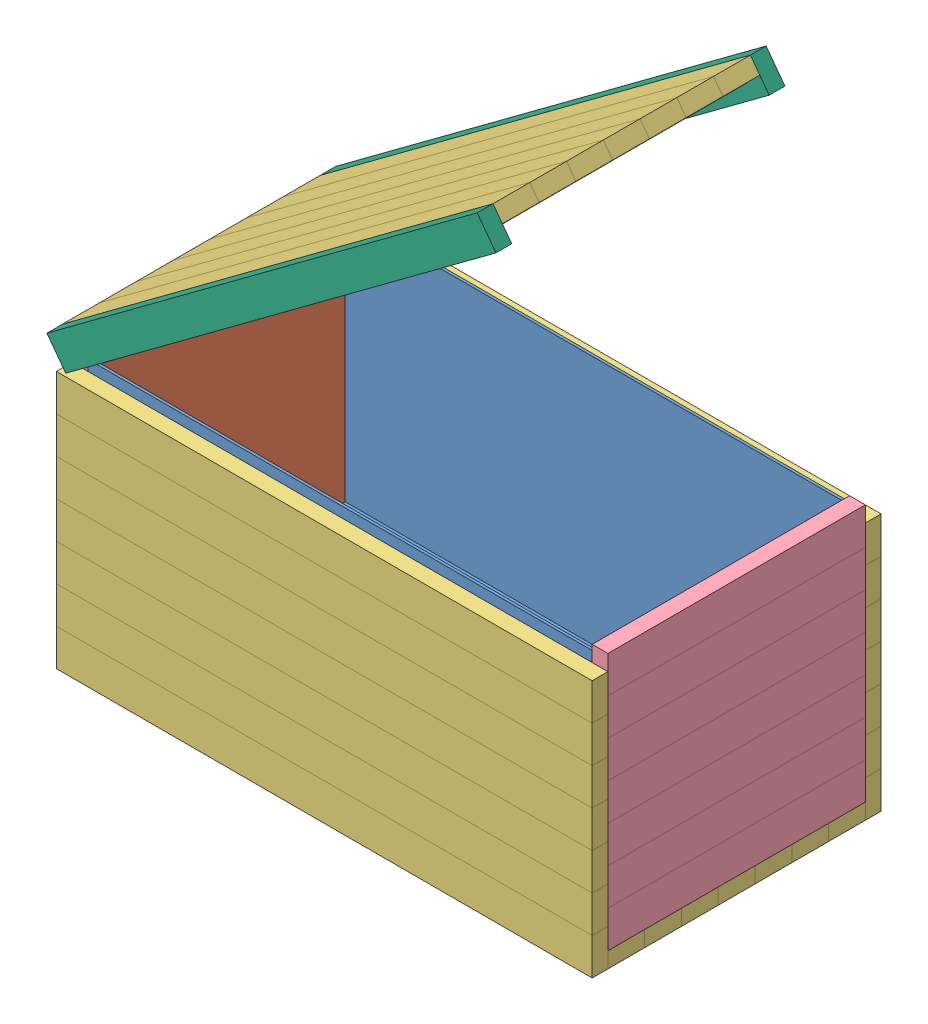
SolidWorks assembly box, configuration Default. Lengths in mm.
Overall size (1331.52 1463.02 698.5).
58 component instances, 8 part files, 31 mates.
Components (placement in the parent):
- plywood_base-1: plywood_base [Default] at (42.8418 78.5863 -75.9974) size (1219.2 6.35 609.6)
- plywood_base-2: plywood_base [Default] at (42.8418 383.3863 228.8026) x (1 0 0) z (0 -1 0) size (1219.2 6.35 609.6)
- plywood_base-3: plywood_base [Default] at (42.8418 383.3863 -380.7974) x (1 0 0) z (0 1 0) size (1219.2 6.35 609.6)
- plywood_short_side-1: plywood_short_side [Default] at (-560.4082 389.7363 -75.9974) x (0 0 1) z (-1 0 0) size (609.6 609.6 6.35)
- plywood_short_side-2: plywood_short_side [Default] at (646.0918 389.7363 -75.9974) x (0 0 -1) z (1 0 0) size (609.6 609.6 6.35)
- long_side-1: long_side [Default] at (-24.755 320.4343 -387.3917) x (1 0 0) z (0 -1 0) size (1295.4 38.1 622.3)
  - 51in_2x4-1: 51in_2x4 [Default] at (-580.1032 -18.8057 235.4979) x (0 0 -1) z (1 0 0) size (88.9 38.1 1295.4)
  - 51in_2x4-2: 51in_2x4 [Default] at (-580.1032 -18.8057 146.5979) x (0 0 -1) z (1 0 0) size (88.9 38.1 1295.4)
  - 51in_2x4-3: 51in_2x4 [Default] at (715.2968 -18.8057 -297.9021) x (0 0 1) z (-1 0 0) size (88.9 38.1 1295.4)
  - 51in_2x4-4: 51in_2x4 [Default] at (715.2968 -18.8057 57.6979) x (0 0 1) z (-1 0 0) size (88.9 38.1 1295.4)
  - 51in_2x4-5: 51in_2x4 [Default] at (715.2968 -18.8057 -31.2021) x (0 0 1) z (-1 0 0) size (88.9 38.1 1295.4)
  - 51in_2x4-6: 51in_2x4 [Default] at (715.2968 -18.8057 -120.1021) x (0 0 1) z (-1 0 0) size (88.9 38.1 1295.4)
  - 51in_2x4-7: 51in_2x4 [Default] at (715.2968 -18.8057 -209.0021) x (0 0 1) z (-1 0 0) size (88.9 38.1 1295.4)
- long_side-2: long_side [Default] at (-24.755 382.8384 235.3968) x (1 0 0) z (0 1 0) size (1295.4 38.1 622.3)
  - 51in_2x4-1: 51in_2x4 [Default] at (-580.1032 -18.8057 235.4979) x (0 0 -1) z (1 0 0) size (88.9 38.1 1295.4)
  - 51in_2x4-2: 51in_2x4 [Default] at (-580.1032 -18.8057 146.5979) x (0 0 -1) z (1 0 0) size (88.9 38.1 1295.4)
  - 51in_2x4-3: 51in_2x4 [Default] at (715.2968 -18.8057 -297.9021) x (0 0 1) z (-1 0 0) size (88.9 38.1 1295.4)
  - 51in_2x4-4: 51in_2x4 [Default] at (715.2968 -18.8057 57.6979) x (0 0 1) z (-1 0 0) size (88.9 38.1 1295.4)
  - 51in_2x4-5: 51in_2x4 [Default] at (715.2968 -18.8057 -31.2021) x (0 0 1) z (-1 0 0) size (88.9 38.1 1295.4)
  - 51in_2x4-6: 51in_2x4 [Default] at (715.2968 -18.8057 -120.1021) x (0 0 1) z (-1 0 0) size (88.9 38.1 1295.4)
  - 51in_2x4-7: 51in_2x4 [Default] at (715.2968 -18.8057 -209.0021) x (0 0 1) z (-1 0 0) size (88.9 38.1 1295.4)
- long_side-3: long_side [Default] at (-24.755 78.3421 -44.7953) size (1295.4 38.1 622.3)
  - 51in_2x4-1: 51in_2x4 [Default] at (-580.1032 -18.8057 235.4979) x (0 0 -1) z (1 0 0) size (88.9 38.1 1295.4)
  - 51in_2x4-2: 51in_2x4 [Default] at (-580.1032 -18.8057 146.5979) x (0 0 -1) z (1 0 0) size (88.9 38.1 1295.4)
  - 51in_2x4-3: 51in_2x4 [Default] at (715.2968 -18.8057 -297.9021) x (0 0 1) z (-1 0 0) size (88.9 38.1 1295.4)
  - 51in_2x4-4: 51in_2x4 [Default] at (715.2968 -18.8057 57.6979) x (0 0 1) z (-1 0 0) size (88.9 38.1 1295.4)
  - 51in_2x4-5: 51in_2x4 [Default] at (715.2968 -18.8057 -31.2021) x (0 0 1) z (-1 0 0) size (88.9 38.1 1295.4)
  - 51in_2x4-6: 51in_2x4 [Default] at (715.2968 -18.8057 -120.1021) x (0 0 1) z (-1 0 0) size (88.9 38.1 1295.4)
  - 51in_2x4-7: 51in_2x4 [Default] at (715.2968 -18.8057 -209.0021) x (0 0 1) z (-1 0 0) size (88.9 38.1 1295.4)
- short_side-2: short_side [Default] at (300.1716 281.9142 -332.5082) x (0 -1 0) z (0 0 1) size (622.3 38.1 622.3)
  - 24in_2x4-1: 24in_2x4 [Default] at (-374.5222 371.3202 -54.6392) size (88.9 38.1 622.3)
  - 24in_2x4-2: 24in_2x4 [Default] at (-285.6222 371.3202 -54.6392) size (88.9 38.1 622.3)
  - 24in_2x4-3: 24in_2x4 [Default] at (-196.7222 371.3202 -54.6392) size (88.9 38.1 622.3)
  - 24in_2x4-4: 24in_2x4 [Default] at (-107.8222 371.3202 -54.6392) size (88.9 38.1 622.3)
  - 24in_2x4-5: 24in_2x4 [Default] at (69.9778 371.3202 -54.6392) size (88.9 38.1 622.3)
  - 24in_2x4-6: 24in_2x4 [Default] at (158.8778 371.3202 -54.6392) size (88.9 38.1 622.3)
  - 24in_2x4-8: 24in_2x4 [Default] at (-18.9222 371.3202 -54.6392) size (88.9 38.1 622.3)
- lid-1: lid [Default] at (-111.6526 1036.7887 -32.7455) x (0.803005 0.595972 0) z (0 0 1) size (1295.4 76.2 698.5)
  - plywood_lid-1: plywood_lid [Default] at (50.5401 17.8556 -38.8001) size (1219.2 6.35 622.3)
  - long_side-1: long_side [Default] at (-16.1318 62.0613 -12.0499) size (1295.4 38.1 622.3)
    - 51in_2x4-1: 51in_2x4 [Default] at (-580.1032 -18.8057 235.4979) x (0 0 -1) z (1 0 0) size (88.9 38.1 1295.4)
    - 51in_2x4-2: 51in_2x4 [Default] at (-580.1032 -18.8057 146.5979) x (0 0 -1) z (1 0 0) size (88.9 38.1 1295.4)
    - 51in_2x4-3: 51in_2x4 [Default] at (715.2968 -18.8057 -297.9021) x (0 0 1) z (-1 0 0) size (88.9 38.1 1295.4)
    - 51in_2x4-4: 51in_2x4 [Default] at (715.2968 -18.8057 57.6979) x (0 0 1) z (-1 0 0) size (88.9 38.1 1295.4)
    - 51in_2x4-5: 51in_2x4 [Default] at (715.2968 -18.8057 -31.2021) x (0 0 1) z (-1 0 0) size (88.9 38.1 1295.4)
    - 51in_2x4-6: 51in_2x4 [Default] at (715.2968 -18.8057 -120.1021) x (0 0 1) z (-1 0 0) size (88.9 38.1 1295.4)
    - 51in_2x4-7: 51in_2x4 [Default] at (715.2968 -18.8057 -209.0021) x (0 0 1) z (-1 0 0) size (88.9 38.1 1295.4)
  - 51in_3in_1-5in-1: 51in_3in_1-5in [Default] at (-596.235 24.2056 -373.452) x (0 1 0) z (1 0 0) size (76.2 38.1 1295.4)
  - 51in_3in_1-5in-2: 51in_3in_1-5in [Default] at (-596.235 24.2056 286.948) x (0 -1 0) z (1 0 0) size (76.2 38.1 1295.4)
- short_side_ubolt-1: short_side_ubolt [Default] at (-957.1284 281.9142 -332.5082) x (0 -1 0) z (0 0 1) size (622.3 38.1 622.3)
  - 24in_2x4-1: 24in_2x4 [Default] at (-374.5222 371.3202 -54.6392) size (88.9 38.1 622.3)
  - 24in_2x4-2: 24in_2x4 [Default] at (-285.6222 371.3202 -54.6392) size (88.9 38.1 622.3)
  - 24in_2x4-3: 24in_2x4 [Default] at (-196.7222 371.3202 -54.6392) size (88.9 38.1 622.3)
  - 24in_2x4-4: 24in_2x4 [Default] at (-107.8222 371.3202 -54.6392) size (88.9 38.1 622.3)
  - 24in_2x4-5: 24in_2x4 [Default] at (69.9778 371.3202 -54.6392) size (88.9 38.1 622.3)
  - 24in_2x4-6: 24in_2x4 [Default] at (158.8778 371.3202 -54.6392) size (88.9 38.1 622.3)
  - 24in_2x4_ubolt-1: 24in_2x4_ubolt [Default] at (-18.9222 371.3202 -54.6392) size (88.9 38.1 622.3)
- ubolt-1: ubolt [8896T119] at (-583.827 300.8363 -75.9974) x (0 0 -1) z (0 1 0) size (50.8 57.15 19.05)
Mates (geometry in assembly coordinates):
- Coincident3: coincident anti-aligned: plane of plywood_base-1 through (652.4418 78.5863 228.8026) normal (0 -1 0); plane of long_side-3/51in_2x4-4 through (-604.8582 78.5863 -31.5474) normal (0 1 0)
- Parallel1: parallel aligned: plane of plywood_base-1 through (652.4418 84.9363 -380.7974) normal (1 0 0); plane of long_side-3/51in_2x4-4 through (690.5418 40.4863 57.3526) normal (1 0 0)
- Coincident5: coincident aligned: line of long_side-3/51in_2x4-4 through (690.5418 78.5863 57.3526) axis (0 0 -1); line of short_side-2/24in_2x4-6 through (690.5418 78.5863 235.1526) axis (0 0 -1)
- Coincident6: coincident anti-aligned: plane of long_side-3/51in_2x4-1 through (690.5418 78.5863 235.1526) normal (0 1 0); plane of short_side-2/24in_2x4-6 through (690.5418 78.5863 235.1526) normal (0 -1 0)
- Coincident7: coincident anti-aligned: plane of plywood_base-1 through (652.4418 84.9363 -380.7974) normal (1 0 0); plane of short_side-2/24in_2x4-6 through (652.4418 167.4863 235.1526) normal (-1 0 0)
- Coincident8: coincident aligned: plane of plywood_base-1 through (-566.7582 84.9363 -380.7974) normal (-1 0 0); plane of plywood_base-2 through (-566.7582 688.1863 235.1526) normal (-1 0 0)
- Coincident11: coincident anti-aligned: plane of plywood_base-1 through (-566.7582 84.9363 -380.7974) normal (0 0 -1); plane of plywood_base-3 through (652.4418 688.1863 -380.7974) normal (0 0 1)
- Coincident12: coincident anti-aligned: plane of plywood_short_side-2 through (652.4418 84.9363 -380.7974) normal (1 0 0); plane of short_side-2/24in_2x4-2 through (652.4418 611.9863 235.1526) normal (-1 0 0)
- Coincident14: coincident anti-aligned: plane of plywood_base-1 through (652.4418 84.9363 228.8026) normal (0 1 0); plane of plywood_short_side-1 through (-566.7582 84.9363 -380.7974) normal (0 -1 0)
- Coincident15: coincident anti-aligned: line of plywood_base-1 through (652.4418 84.9363 -380.7974) axis (-1 0 0); line of plywood_short_side-1 through (-566.7582 84.9363 -380.7974) axis (1 0 0)
- Coincident24: coincident anti-aligned: plane of plywood_base-1 through (-566.7582 84.9363 228.8026) normal (0 0 1); plane of plywood_base-2 through (652.4418 78.5863 228.8026) normal (0 0 -1)
- Coincident25: coincident aligned: line of plywood_base-1 through (-566.7582 78.5863 228.8026) axis (1 0 0); line of plywood_base-2 through (-566.7582 78.5863 228.8026) axis (1 0 0)
- Coincident26: coincident aligned: plane of plywood_base-1 through (652.4418 78.5863 228.8026) normal (0 -1 0); plane of plywood_base-3 through (-566.7582 78.5863 -387.1474) normal (0 -1 0)
- Coincident27: coincident aligned: plane of plywood_base-3 through (652.4418 78.5863 -387.1474) normal (1 0 0); plane of plywood_short_side-2 through (652.4418 84.9363 -380.7974) normal (1 0 0)
- Coincident28: coincident aligned: plane of plywood_base-2 through (652.4418 78.5863 235.1526) normal (0 0 1); plane of long_side-3/51in_2x4-1 through (690.5418 78.5863 235.1526) normal (0 0 1)
- Coincident29: coincident anti-aligned: plane of plywood_base-3 through (652.4418 688.1863 -387.1474) normal (0 0 -1); plane of long_side-1/51in_2x4-5 through (-604.8582 396.0863 -387.1474) normal (0 0 1)
- Coincident30: coincident anti-aligned: plane of plywood_base-2 through (652.4418 78.5863 235.1526) normal (0 0 1); plane of long_side-2/51in_2x4-5 through (-604.8582 307.1863 235.1526) normal (0 0 -1)
- Coincident31: coincident aligned: plane of long_side-1/51in_2x4-1 through (690.5418 40.4863 -387.1474) normal (0 -1 0); plane of long_side-3/51in_2x4-3 through (-604.8582 40.4863 -387.1474) normal (0 -1 0)
- Coincident32: coincident aligned: plane of long_side-1/51in_2x4-1 through (690.5418 129.3863 -425.2474) normal (1 0 0); plane of long_side-3/51in_2x4-3 through (690.5418 40.4863 -298.2474) normal (1 0 0)
- Coincident33: coincident anti-aligned: plane of long_side-1/51in_2x4-5 through (-604.8582 396.0863 -387.1474) normal (0 0 1); plane of short_side-2/24in_2x4-4 through (652.4418 345.2863 -387.1474) normal (0 0 -1)
- Coincident34: coincident aligned: plane of long_side-2/51in_2x4-3 through (690.5418 129.3863 273.2526) normal (1 0 0); plane of long_side-3/51in_2x4-1 through (690.5418 40.4863 146.2526) normal (1 0 0)
- Coincident35: coincident anti-aligned: line of long_side-2/51in_2x4-3 through (690.5418 40.4863 235.1526) axis (0 0 1); line of long_side-3/51in_2x4-1 through (690.5418 40.4863 235.1526) axis (0 0 -1)
- Coincident39: coincident aligned: plane of long_side-2/51in_2x4-1 through (690.5418 662.7863 273.2526) normal (0 0 1); plane of lid-1/51in_3in_1-5in-2 through (412.648 1503.5032 273.2526) normal (0 0 1)
- Coincident40: coincident anti-aligned: plane of long_side-3/51in_2x4-7 through (-604.8582 78.5863 -298.2474) normal (0 1 0); plane of short_side_ubolt-1/24in_2x4-6 through (-566.7582 78.5863 235.1526) normal (0 -1 0)
- Coincident41: coincident anti-aligned: plane of plywood_short_side-1 through (-566.7582 84.9363 228.8026) normal (-1 0 0); plane of short_side_ubolt-1/24in_2x4-3 through (-566.7582 523.0863 235.1526) normal (1 0 0)
- Coincident42: coincident anti-aligned: plane of long_side-2/51in_2x4-5 through (-604.8582 307.1863 235.1526) normal (0 0 -1); plane of short_side_ubolt-1/24in_2x4-3 through (-604.8582 434.1863 235.1526) normal (0 0 1)
- Coincident43: coincident anti-aligned: line of lid-1/long_side-1/51in_2x4-5 through (-604.8582 700.8863 -120.4474) axis (0 0 1); line of short_side_ubolt-1/24in_2x4-1 through (-604.8582 700.8863 235.1526) axis (0 0 -1)
- Coincident44: coincident aligned: circle of short_side_ubolt-1/24in_2x4_ubolt-1; cylinder of ubolt-1 through (-620.3395 300.8363 -93.4599) axis (1 0 0) radius 3.175
- Coincident45: coincident aligned: circle of short_side_ubolt-1/24in_2x4_ubolt-1; cylinder of ubolt-1 through (-620.3395 300.8363 -58.5349) axis (1 0 0) radius 3.175
- Coincident46: coincident aligned: plane of short_side_ubolt-1/24in_2x4_ubolt-1 through (-604.8582 345.2863 235.1526) normal (-1 0 0); plane of ubolt-1 through (-604.8582 291.3113 -50.5974) normal (-1 0 0)
- Coincident47: coincident aligned: plane of long_side-3/51in_2x4-5 through (-604.8582 40.4863 -31.5474) normal (-1 0 0); plane of short_side_ubolt-1/24in_2x4-6 through (-604.8582 167.4863 235.1526) normal (-1 0 0)
